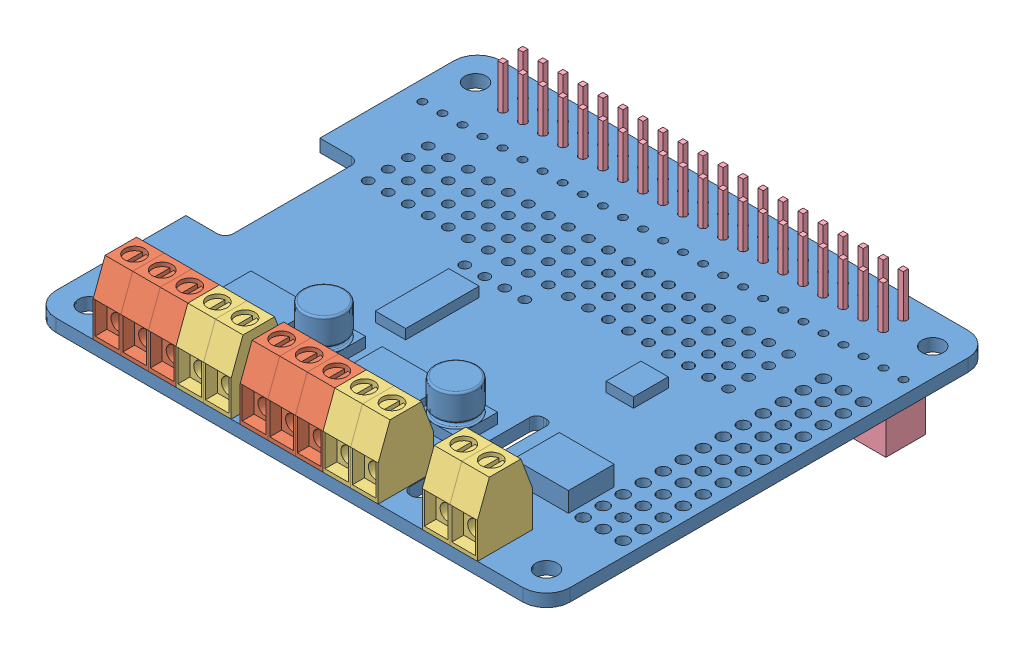
SolidWorks assembly AssembledAdafruitStepperHat, configuration Default. Lengths in mm.
Overall size (65.25 21.15 56.5).
7 component instances, 4 part files, 18 mates.
Components (placement in the parent):
- AdafruitStepperHat-1: AdafruitStepperHat [Default] at (71.9514 28.5864 47.8631) size (65.25 6.9 56.5)
- terminal block_3-4: terminal block_3 [기본] at (33.831 30.1864 69.9597) x (-1 0 0) z (0 0 -1) size (10.5 12 7)
- terminal block_3-5: terminal block_3 [기본] at (15.181 30.1864 69.9597) x (-1 0 0) z (0 0 -1) size (10.5 12 7)
- terminal block_2-4: terminal block_2 [기본] at (40.831 30.1864 69.9597) x (-1 0 0) z (0 0 -1) size (7 12 7)
- terminal block_2-5: terminal block_2 [기본] at (53.431 30.1864 69.9597) x (-1 0 0) z (0 0 -1) size (7 12 7)
- terminal block_2-6: terminal block_2 [기본] at (22.181 30.1864 69.9597) x (-1 0 0) z (0 0 -1) size (7 12 7)
- 40pin-1: 40pin [Default] at (3.861 28.5864 21.9797) x (0 0 -1) z (-1 0 0) size (5 18.05 51.4)
Mates (geometry in assembly coordinates):
- Concentric19: concentric aligned: circle of AdafruitStepperHat-1; cylinder of terminal block_2-4 through (39.081 26.6864 73.4597) axis (0 1 0) radius 0.325
- Concentric20: concentric aligned: circle of AdafruitStepperHat-1; cylinder of terminal block_2-4 through (35.581 26.6864 73.4597) axis (0 1 0) radius 0.325
- Coincident2: coincident anti-aligned: plane of AdafruitStepperHat-1 through (71.9514 30.1864 47.8631) normal (0 1 0); plane of terminal block_2-4 through (33.831 30.1864 69.9597) normal (0 -1 0)
- Concentric21: concentric aligned: circle of AdafruitStepperHat-1; cylinder of terminal block_3-4 through (32.081 26.6864 73.4597) axis (0 1 0) radius 0.325
- Concentric22: concentric aligned: circle of AdafruitStepperHat-1; cylinder of terminal block_3-4 through (25.081 26.6864 73.4597) axis (0 1 0) radius 0.325
- Coincident3: coincident anti-aligned: plane of AdafruitStepperHat-1 through (71.9514 30.1864 47.8631) normal (0 1 0); plane of terminal block_3-4 through (23.331 30.1864 69.9597) normal (0 -1 0)
- Concentric23: concentric aligned: circle of AdafruitStepperHat-1; cylinder of terminal block_2-6 through (20.431 26.6864 73.4597) axis (0 1 0) radius 0.325
- Concentric24: concentric aligned: circle of AdafruitStepperHat-1; cylinder of terminal block_2-6 through (16.931 26.6864 73.4597) axis (0 1 0) radius 0.325
- Coincident4: coincident anti-aligned: plane of AdafruitStepperHat-1 through (71.9514 30.1864 47.8631) normal (0 1 0); plane of terminal block_2-6 through (15.181 30.1864 69.9597) normal (0 -1 0)
- Concentric25: concentric aligned: circle of AdafruitStepperHat-1; cylinder of terminal block_3-5 through (13.431 26.6864 73.4597) axis (0 1 0) radius 0.325
- Concentric26: concentric aligned: circle of AdafruitStepperHat-1; cylinder of terminal block_3-5 through (6.431 26.6864 73.4597) axis (0 1 0) radius 0.325
- Coincident6: coincident anti-aligned: plane of AdafruitStepperHat-1 through (71.9514 30.1864 47.8631) normal (0 1 0); plane of terminal block_3-5 through (4.681 30.1864 69.9597) normal (0 -1 0)
- Concentric27: concentric aligned: circle of AdafruitStepperHat-1; cylinder of terminal block_2-5 through (51.681 26.6864 73.4597) axis (0 1 0) radius 0.325
- Concentric28: concentric aligned: circle of AdafruitStepperHat-1; cylinder of terminal block_2-5 through (48.181 26.6864 73.4597) axis (0 1 0) radius 0.325
- Coincident8: coincident anti-aligned: plane of AdafruitStepperHat-1 through (71.9514 30.1864 47.8631) normal (0 1 0); plane of terminal block_2-5 through (49.931 30.1864 69.9597) normal (0 -1 0)
- Concentric34: concentric anti-aligned: line of 40pin-1 through (5.431 35.9364 23.2097) axis (0 -1 0); circle of AdafruitStepperHat-1
- Concentric35: concentric aligned: circle of AdafruitStepperHat-1; line of 40pin-1 through (53.691 28.2364 25.7497) axis (0 1 0)
- Coincident10: coincident anti-aligned: plane of AdafruitStepperHat-1 through (71.9514 28.5864 47.8631) normal (0 -1 0); plane of 40pin-1 through (29.561 28.5864 24.4797) normal (0 1 0)
